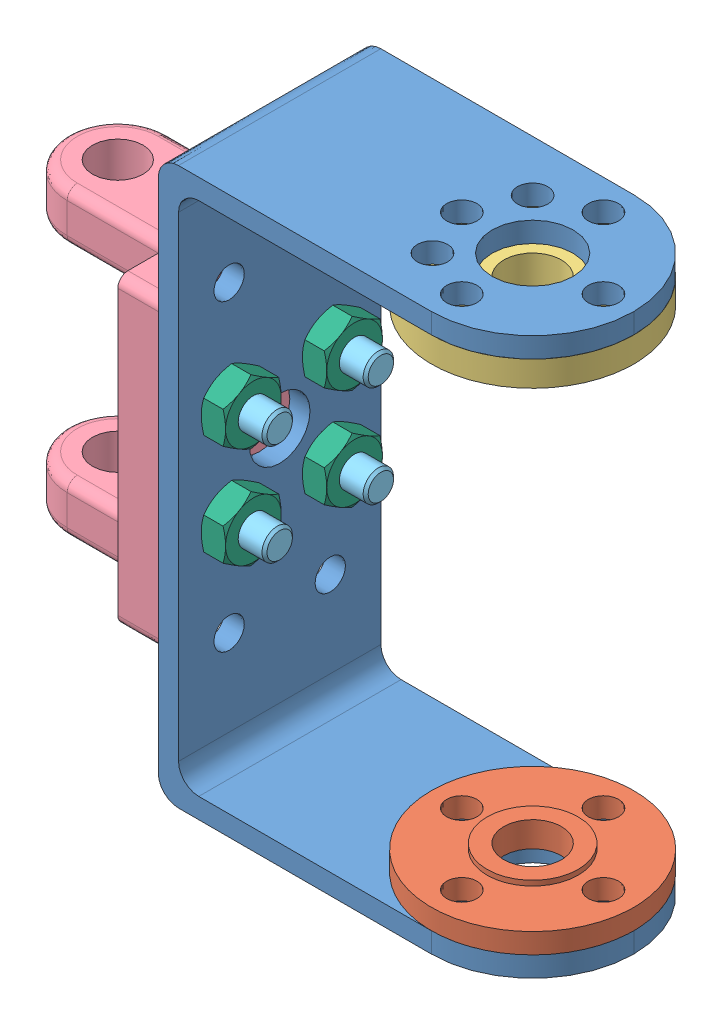
SolidWorks assembly moteur-bras-v2, configuration Défaut. Lengths in mm.
Overall size (56 55 20).
12 component instances, 6 part files, 28 mates.
Components (placement in the parent):
- moteur-support-mobile-v2-1: moteur-support-mobile-v2 [Défaut] at (18.386 -2.2808 45) size (37 55 20)
- moteur-platine_libre-1: moteur-platine_libre [Défaut] at (8.386 -27.7808 55) x (1 0 0) z (0 1 0) size (20 20 2.5)
- moteur-platine_moteur-1: moteur-platine_moteur [Défaut] at (8.386 23.2192 55) x (1 0 0) z (0 -1 0) size (20 20 4.5)
- support-fourchette-chc_m3-1: support-fourchette-chc_m3 [Défaut] at (-32.614 -2.2808 55) x (0 1 0) z (0 0 1) size (30 19 20)
- vis-chc-1: vis-chc [Vis CHC M3x8] at (-19.614 2.7192 50) x (0 0.164744 0.986336) z (0 -0.986336 0.164744) size (5.5 11 5.5)
- ecrou-h-1: ecrou-h [6012 HU M3] at (-16.614 2.7192 50) x (0 0.866025 0.5) z (0 -0.5 0.866025) size (5.5 2.4 6.35)
- ecrou-h-2: ecrou-h [6012 HU M3] at (-14.214 2.7192 60) x (0 -0.866025 -0.5) z (0 -0.5 0.866025) size (5.5 2.4 6.35)
- ecrou-h-3: ecrou-h [6012 HU M3] at (-14.214 -7.2808 50) x (0 -0.866025 -0.5) z (0 -0.5 0.866025) size (5.5 2.4 6.35)
- ecrou-h-4: ecrou-h [6012 HU M3] at (-14.214 -7.2808 60) x (0 -0.866025 -0.5) z (0 -0.5 0.866025) size (5.5 2.4 6.35)
- vis-chc-2: vis-chc [Vis CHC M3x8] at (-19.614 2.7192 60) x (0 -0.933966 -0.357361) z (0 0.357361 -0.933966) size (5.5 11 5.5)
- vis-chc-3: vis-chc [Vis CHC M3x8] at (-19.614 -7.2808 60) x (0 0.351541 0.936173) z (0 -0.936173 0.351541) size (5.5 11 5.5)
- vis-chc-4: vis-chc [Vis CHC M3x8] at (-19.614 -7.2808 50) x (0 -0.47591 0.879494) z (0 -0.879494 -0.47591) size (5.5 11 5.5)
Mates (geometry in assembly coordinates):
- Coïncidente1: coincident anti-aligned: plane of moteur-support-mobile-v2-1 through (-14.614 23.2192 65) normal (0 -1 0); plane of moteur-platine_moteur-1 through (8.386 23.2192 55) normal (0 1 0)
- Coïncidente2: coincident anti-aligned: plane of moteur-support-mobile-v2-1 through (18.386 -27.7808 65) normal (0 1 0); plane of moteur-platine_libre-1 through (8.386 -27.7808 55) normal (0 -1 0)
- Coaxiale1: concentric aligned: cylinder of moteur-support-mobile-v2-1 through (1.386 -29.7808 55) axis (0 1 0) radius 1.5; cylinder of moteur-platine_libre-1 through (1.386 -27.7808 55) axis (0 1 0) radius 1.5
- Coaxiale2: concentric anti-aligned: cylinder of moteur-support-mobile-v2-1 through (8.386 -29.7808 55) axis (0 1 0) radius 4; cylinder of moteur-platine_libre-1 through (8.386 -25.7808 55) axis (0 -1 0) radius 2.85
- Coaxiale3: concentric aligned: cylinder of moteur-support-mobile-v2-1 through (8.386 -29.7808 55) axis (0 1 0) radius 4; cylinder of moteur-platine_moteur-1 through (8.386 20.7192 55) axis (0 1 0) radius 2.85
- Coaxiale4: concentric anti-aligned: cylinder of moteur-support-mobile-v2-1 through (8.386 -29.7808 62) axis (0 1 0) radius 1.5; cylinder of moteur-platine_moteur-1 through (8.386 23.2192 62) axis (0 -1 0) radius 1.5
- Coïncidente3: coincident anti-aligned: plane of moteur-support-mobile-v2-1 through (-18.614 23.2192 65) normal (-1 0 0); plane of support-fourchette-ecrou_m2-1 through (-18.614 -2.2808 55) normal (1 0 0)
- Coaxiale5: concentric aligned: cylinder of moteur-support-mobile-v2-1 through (18.387 2.7192 50) axis (-1 0 0) radius 1.5; cylinder of support-fourchette-ecrou_m2-1 through (-18.613 2.7192 50) axis (-1 0 0) radius 1.6
- Coaxiale6: concentric aligned: cylinder of support-fourchette-chc_m3-1 through (-18.613 2.7192 50) axis (-1 0 0) radius 1.6; cylinder of vis-chc-m2-1 through (-11.614 2.7192 50) axis (-1 0 0) radius 1.5
- Coïncidente4: coincident anti-aligned: plane of moteur-support-mobile-v2-1 through (-16.614 -25.7808 65) normal (1 0 0); plane of ecrou-h-m2-1 through (-16.614 5.8946 50) normal (-1 0 0)
- Coaxiale7: concentric aligned: cylinder of moteur-support-mobile-v2-1 through (18.387 2.7192 50) axis (-1 0 0) radius 1.5; cylinder of ecrou-h-m2-1 through (-14.214 2.7192 50) axis (-1 0 0) radius 1.2295
- Parallèle1: parallel aligned: plane of moteur-support-mobile-v2-1 through (-16.614 23.2192 45) normal (0 0 -1); plane of ecrou-h-m2-1 through (-14.214 4.3069 47.25) normal (0 0 -1)
- Coaxiale8: concentric aligned: cylinder of moteur-support-mobile-v2-1 through (18.387 2.7192 60) axis (-1 0 0) radius 1.5; cylinder of vis-chc-2 through (-11.614 2.7192 60) axis (-1 0 0) radius 1.5
- Coaxiale9: concentric aligned: cylinder of moteur-support-mobile-v2-1 through (18.387 -7.2808 60) axis (-1 0 0) radius 1.5; cylinder of vis-chc-3 through (-11.614 -7.2808 60) axis (-1 0 0) radius 1.5
- Coaxiale10: concentric aligned: cylinder of moteur-support-mobile-v2-1 through (18.387 -7.2808 50) axis (-1 0 0) radius 1.5; cylinder of vis-chc-4 through (-11.614 -7.2808 50) axis (-1 0 0) radius 1.5
- Coïncidente8: coincident anti-aligned: plane of support-fourchette-chc_m3-1 through (-19.614 2.7192 50) normal (-1 0 0); plane of vis-chc-1 through (-19.614 2.7192 50) normal (1 0 0)
- Coïncidente9: coincident anti-aligned: plane of support-fourchette-chc_m3-1 through (-19.614 2.7192 60) normal (-1 0 0); plane of vis-chc-2 through (-19.614 2.7192 60) normal (1 0 0)
- Coïncidente10: coincident anti-aligned: plane of support-fourchette-chc_m3-1 through (-19.614 -7.2808 60) normal (-1 0 0); plane of vis-chc-3 through (-19.614 -7.2808 60) normal (1 0 0)
- Coïncidente11: coincident anti-aligned: plane of support-fourchette-chc_m3-1 through (-19.614 -7.2808 50) normal (-1 0 0); plane of vis-chc-4 through (-19.614 -7.2808 50) normal (1 0 0)
- Coaxiale11: concentric anti-aligned: cylinder of ecrou-h-2 through (-16.614 2.7192 60) axis (1 0 0) radius 1.2295; cylinder of vis-chc-2 through (-11.614 2.7192 60) axis (-1 0 0) radius 1.5
- Coaxiale12: concentric anti-aligned: cylinder of ecrou-h-3 through (-16.614 -7.2808 50) axis (1 0 0) radius 1.2295; cylinder of vis-chc-4 through (-11.614 -7.2808 50) axis (-1 0 0) radius 1.5
- Coaxiale13: concentric anti-aligned: cylinder of ecrou-h-4 through (-16.614 -7.2808 60) axis (1 0 0) radius 1.2295; cylinder of vis-chc-3 through (-11.614 -7.2808 60) axis (-1 0 0) radius 1.5
- Coïncidente12: coincident anti-aligned: plane of moteur-support-mobile-v2-1 through (-16.614 -25.7808 65) normal (1 0 0); plane of ecrou-h-4 through (-16.614 -8.8685 57.25) normal (-1 0 0)
- Coïncidente13: coincident anti-aligned: plane of moteur-support-mobile-v2-1 through (-16.614 -25.7808 65) normal (1 0 0); plane of ecrou-h-3 through (-16.614 -8.8685 47.25) normal (-1 0 0)
- Coïncidente14: coincident anti-aligned: plane of moteur-support-mobile-v2-1 through (-16.614 -25.7808 65) normal (1 0 0); plane of ecrou-h-2 through (-16.614 1.1315 57.25) normal (-1 0 0)
- Parallèle2: parallel aligned: plane of moteur-support-mobile-v2-1 through (-16.614 23.2192 65) normal (0 0 1); plane of ecrou-h-2 through (-16.614 4.3069 62.75) normal (0 0 1)
- Parallèle3: parallel aligned: plane of moteur-support-mobile-v2-1 through (-16.614 23.2192 65) normal (0 0 1); plane of ecrou-h-4 through (-16.614 -5.6931 62.75) normal (0 0 1)
- Parallèle4: parallel aligned: plane of moteur-support-mobile-v2-1 through (-16.614 23.2192 45) normal (0 0 -1); plane of ecrou-h-3 through (-16.614 -8.8685 47.25) normal (0 0 -1)
